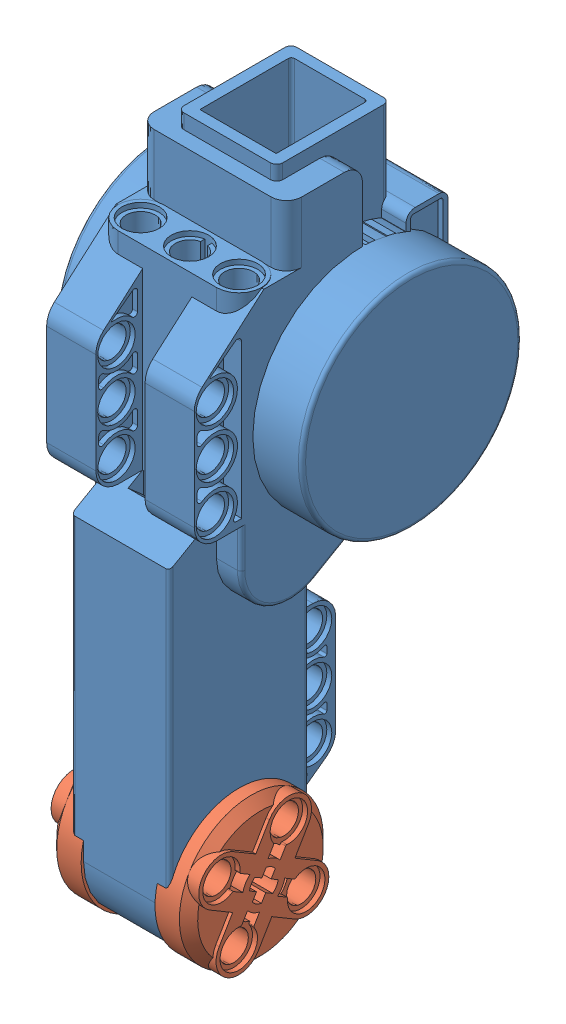
SolidWorks assembly NXT Motor, configuration Default. Lengths in mm.
Overall size (40.3 113.13 50.34).
3 component instances, 2 part files, 0 mates.
Components (placement in the parent):
- NXT Motor Body-1: NXT Motor Body [Default] at origin size (40.3 108.38 45.58)
- NXT Motor Wheel-1: NXT Motor Wheel [Default] at (-6.05 0 0) x (0 -0.509274 -0.860605) z (-1 0 0) size (23.58 23.57 6.05)
- NXT Motor Wheel-2: NXT Motor Wheel [Default] at (6.05 0 0) x (0 0.509274 0.860605) z (1 0 0) size (23.58 23.57 6.05)
